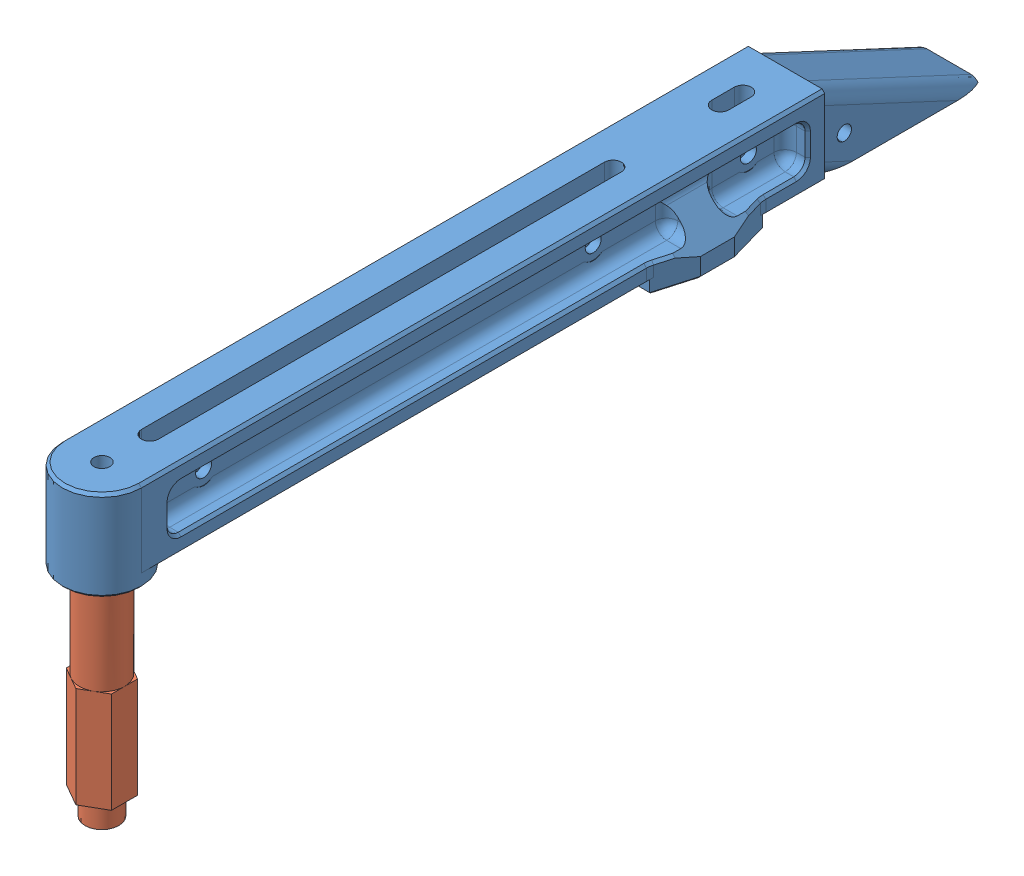
SolidWorks assembly TaperSplineTest, configuration Default. Lengths in mm.
Overall size (28.57 86.15 249.24).
2 component instances, 2 part files, 2 mates.
Components (placement in the parent):
- MBSolidCouplerLargeStock-1: MBSolidCouplerLargeStock [TaperedSpline] at origin size (28.57 25.47 249.24)
- MoveableBallast_OutputShaft-1: MoveableBallast_OutputShaft [TaperedSpline] at (0 -68.6838 192.0875) size (12.7 76.11 14.66)
Mates (geometry in assembly coordinates):
- Concentric2: concentric aligned: cylinder of MBSolidCouplerLargeStock-1 through (0 -11.1125 192.0875) axis (0 -1 0) radius 11.1125; cylinder of MoveableBallast_OutputShaft-1 through (0 0.9122 192.0875) axis (0 -1 0) radius 6.35
- Coincident5: coincident anti-aligned: plane of MBSolidCouplerLargeStock-1 through (3.6775 -14.2875 198.4375) normal (-0.991445 -0.130526 0); plane of MoveableBallast_OutputShaft-1 through (3.7664 -14.9628 199.4208) normal (0.991445 0.130526 0)
